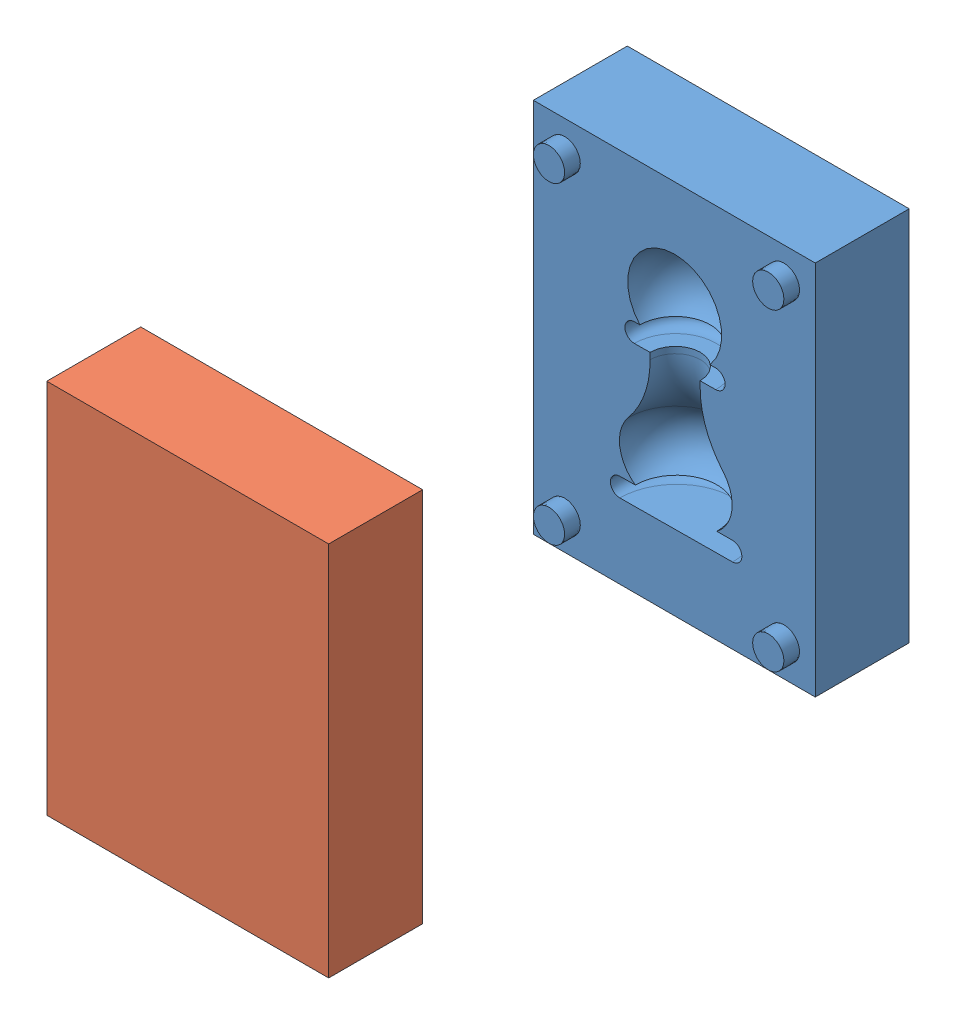
SolidWorks assembly substrac parte extruida, configuration Predeterminado. Lengths in mm.
Overall size (45 60 92.67).
3 component instances, 3 part files, 5 mates.
Components (placement in the parent):
- parte extruida molde-3: parte extruida molde [Predeterminado] at origin size (45 60 17.5)
- pawn-3: pawn [Predeterminado] at (0.3032 -17.9988 15) x (0.999966 0.007979 -0.001912) z (0.001912 0.000015 0.999998) size (21 38 21) (hidden)
- parte corte molde-2: parte corte molde [Predeterminado] at (0 0 92.6666) x (-1 0 0) z (0 0 -1) size (45 60 15)
Mates (geometry in assembly coordinates):
- Distance1: distance = 10 mm: line of assembly; point of pawn-3; line of parte extruida molde-3 through (22.5 30 15) axis (-1 0 0)
- Distance5: distance = 22.5 mm: line of assembly; point of pawn-3; line of parte extruida molde-3 through (-22.5 30 15) axis (0 -1 0)
- Coincident24: coincident: plane of parte extruida molde-3 through (0 0 15) normal (0 0 1); point of pawn-3
- Coincident34: coincident aligned: plane of parte extruida molde-3 through (-22.5 30 15) normal (0 1 0); plane of parte corte molde-2 through (-22.5 30 77.6666) normal (0 1 0)
- Coincident35: coincident aligned: plane of parte extruida molde-3 through (22.5 -30 15) normal (1 0 0); plane of parte corte molde-2 through (22.5 -30 77.6666) normal (1 0 0)
